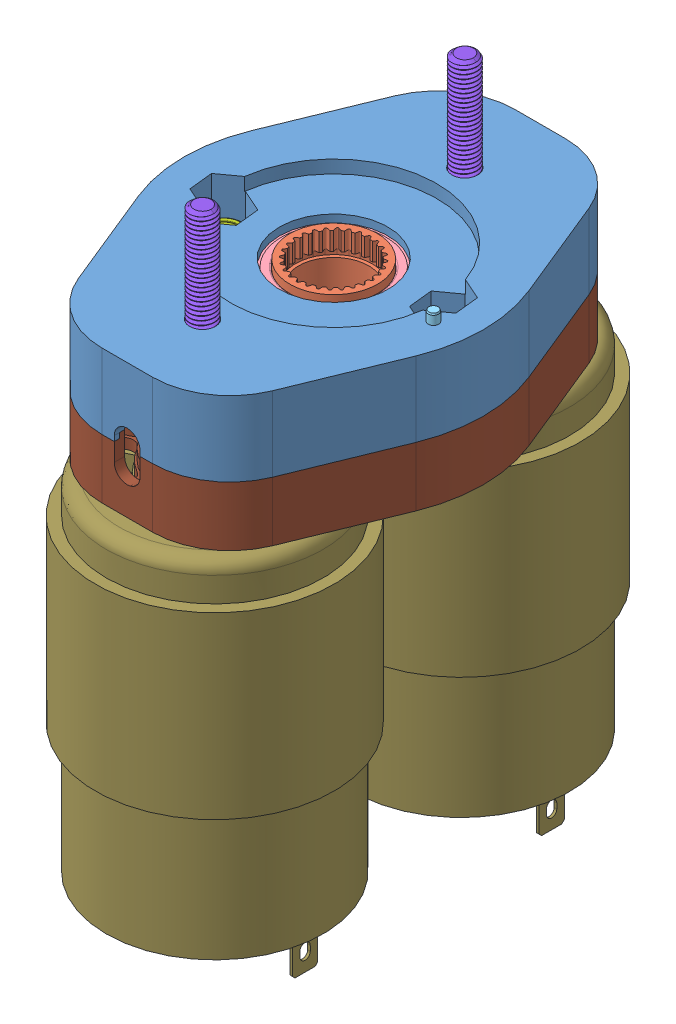
SolidWorks assembly Dual_Motor_Input_with_775_Series (1), configuration Default. Lengths in mm.
Overall size (58 120.42 93.95).
24 component instances, 13 part files, 0 mates.
Components (placement in the parent):
- 217-3141-001 Rev1-1: 217-3141-001 Rev1 [Default] x (0 0 1) z (-1 0 0) size (80 14.5 58)
- 217-3141-007 Rev1_30T 32DP-1: 217-3141-007 Rev1_30T 32DP [Default] at (0 -7.06 0) x (0 -1 0) z (-0.999183 0 0.040426) size (22.38 25.55 25.47)
- 217-3141-006 Rev1_30T 32DP-1: 217-3141-006 Rev1_30T 32DP [Default] at (0.8337 -9.0499 -23.8741) x (-0.095925 0 -0.995389) z (0 -1 0) size (25.47 25.55 10)
- 217-3141-006 Rev1_30T 32DP-2: 217-3141-006 Rev1_30T 32DP [Default] at (0.8337 -9.0499 23.8741) x (-0.001725 0 0.999999) z (0 -1 0) size (25.47 25.55 10)
- 217-2741_1-1: 217-2741_1 [Default] at (0 2.75 0) x (0 -1 0) z (-0.999445 0 -0.033298) size (5 26 26)
- 217-2741_1-2: 217-2741_1 [Default] at (0 -13.25 0) x (0 -1 0) z (-0.537831 0 0.843053) size (5 26 26)
- PINL-M020-006-S-1: PINL-M020-006-S [Default] at (22.7445 5.75 3.4184) x (0 1 0) z (-0.890225 0 0.455522) size (6 2 2)
- SSS1032-0188-ZB-1: SSS1032-0188-ZB [Default] at (0.4848 -10.9249 -27.4949) x (-0.758755 -0.647259 0.073121) z (0.095925 0 0.995389) size (4.91 4.91 5.06)
- SSS1032-0188-ZB-2: SSS1032-0188-ZB [Default] at (0.8274 -10.9249 27.5116) x (0.762269 -0.647259 0.001315) z (0.001725 0 -0.999999) size (4.91 4.91 5.06)
- NUT-832-NYLOCK-1: NUT-832-NYLOCK [Default] at (19.244 -4.75 -2.0226) x (0.913545 0 0.406737) z (-0.406737 0 0.913545) size (10.2 4.9 8.12)
- NUT-832-NYLOCK-2: NUT-832-NYLOCK [Default] at (-19.244 -4.75 2.0226) x (0.912648 0 0.408747) z (-0.408747 0 0.912648) size (10.2 4.9 8.12)
- 91251A346_91251A346-1: 91251A346_91251A346 [Default] at (0 25.975 25.4) x (1 0 0) z (0 1 0) size (7.92 7.92 27.28)
- 91251A346_91251A346-2: 91251A346_91251A346 [Default] at (0 25.975 -25.4) x (1 0 0) z (0 1 0) size (7.92 7.92 27.28)
- SSA_SSAM4-0010ZC)-1: SSA_SSAM4-0010ZC) [Default] at (12.5 -17.25 -23.8887) size (7 14 7)
- SSA_SSA0832-0750ZC)-1: SSA_SSA0832-0750ZC) [Default] at (19.244 -19.2499 -2.0226) x (-0.091926 0 -0.995766) z (-0.995766 0 0.091926) size (6.73 23.11 6.73)
- SSA_SSA0832-0750ZC)-2: SSA_SSA0832-0750ZC) [Default] at (-19.244 -19.2499 2.0226) x (-0.18632 0 -0.982489) z (-0.982489 0 0.18632) size (6.73 23.11 6.73)
- SSA_SSAM4-0010ZC)-2: SSA_SSAM4-0010ZC) [Default] at (-13.6663 -17.2499 23.8741) x (0.677756 0 0.735287) z (-0.735287 0 0.677756) size (7 14 7)
- SSA_SSAM4-0010ZC)-3: SSA_SSAM4-0010ZC) [Default] at (15.3337 -17.2499 23.8741) x (0.994338 0 -0.106265) z (0.106265 0 0.994338) size (7 14 7)
- SSA_SSAM4-0010ZC)-4: SSA_SSAM4-0010ZC) [Default] at (-13.6663 -17.2499 -23.8741) x (0.537906 0 -0.843005) z (0.843005 0 0.537906) size (7 14 7)
- 217-3141-004 Rev1)-1: 217-3141-004 Rev1) [Default] at (0 -12.9999 0) x (0 0 1) z (0 1 0) size (80 58 12.5)
- BB RS775-18V )-1: BB RS775-18V ) [Default] at (0.8337 -19.2499 23.8741) x (0 -1 0) z (0 0 1) size (88 46.2 46.2)
- BB RS775-18V )-2: BB RS775-18V ) [Default] at (0.8337 -19.2499 -23.8741) x (0 -1 0) z (0 0 -1) size (88 46.2 46.2)
- 217-2625-013 Rev1 )-1: 217-2625-013 Rev1 ) [Default] at (0.8337 -10.1999 23.8741) x (1 0 0) z (0 1 0) size (8 7.93 7.5)
- 217-2625-013 Rev1 )-2: 217-2625-013 Rev1 ) [Default] at (0.8337 -10.1999 -23.8741) x (1 0 0) z (0 1 0) size (8 7.93 7.5)
